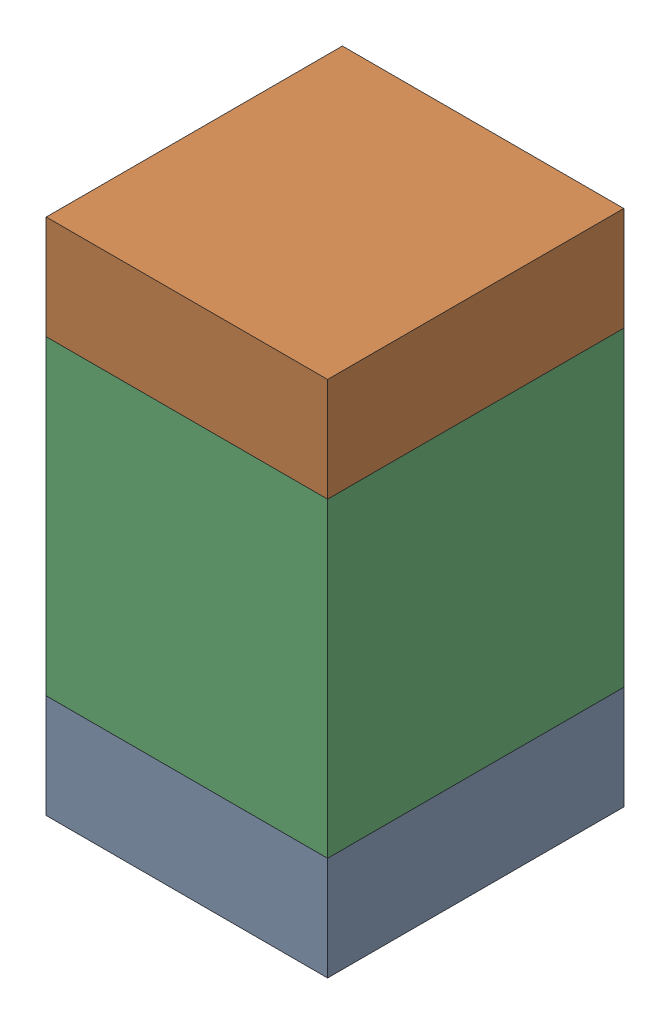
SolidWorks assembly C3-2, configuration Default. Lengths in mm.
Overall size (0.95 1.75 1).
6 component instances, 2 part files, 0 mates.
Components (placement in the parent):
- 959208664-2-1: 959208664-2 [Default] at (146.558 83.0961 0) size (0.95 0.35 1)
  - Extruded-76-1: Extruded-76 [Default] at origin size (0.95 0.35 1)
- 959208664-2-2: 959208664-2 [Default] at (146.558 84.4961 0) size (0.95 0.35 1)
  - Extruded-76-1: Extruded-76 [Default] at origin size (0.95 0.35 1)
- 959208528-2-1: 959208528-2 [Default] at (146.558 83.7961 0) size (0.95 1.05 1)
  - Extruded-77-1: Extruded-77 [Default] at origin size (0.95 1.05 1)
